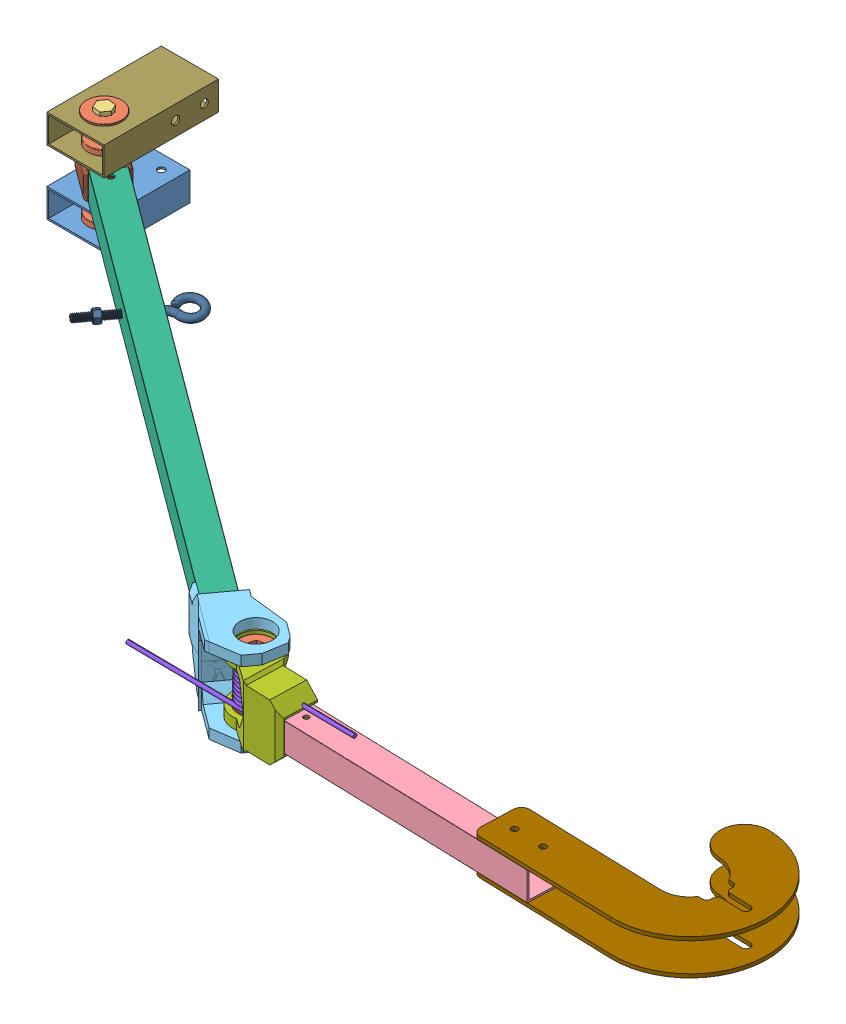
SolidWorks assembly Climber vsomething with fold back, configuration Default. Lengths in mm.
Overall size (917.13 131.37 455.28).
18 component instances, 12 part files, 20 mates.
Components (placement in the parent):
- Climb Mount small-1: Climb Mount small [Default] at origin size (50.8 25.4 76.2)
- am-2986 FR8ZZ Hex Bearing.step-1: am-2986 FR8ZZ Hex Bearing.step [Default] at (0 -6.2967 50.8) x (0.594647 0 -0.803987) z (0 -1 0) size (31.12 31.12 7.93)
- Climb axle-1: Climb axle [Default] at (0 -14.224 50.8) x (0.594647 0 -0.803987) z (0 1 0) size (14.66 12.7 88.9)
- ClimberRev2 back-1: ClimberRev2 back [Default] at (698.9971 17.3884 404.1141) x (0.001343 0.993572 -0.113195) z (0.99993 0 0.011862) size (90.91 362.58 883.75)
  - 1x1x20 box extrusion for climber-4: 1x1x20 box extrusion for climber [Default] at (0.1627 -18.2144 -212.2666) x (0.993572 0.113203 0) z (-0.002183 0.019159 0.999814) size (25.4 25.4 254)
  - Climber Insert Rev3 Outer-3: Climber Insert Rev3 Outer [Default] at (4.2736 -50.8774 -314.6587) x (0.993572 0.113203 0) z (0.066232 -0.581307 -0.810985) size (75.39 53.74 112.86)
  - 1x1x20 box extrusion for climber upper-3: 1x1x20 box extrusion for climber upper [Default] at (25.7469 -43.0175 -269.2161) x (-0.993572 -0.113203 0) z (0.066232 -0.581307 -0.810985) size (25.4 25.4 508)
  - Climber Insert Rev3 Inner-1: Climber Insert Rev3 Inner [Default] at (10.0811 -4.6349 -161.6957) x (0.993572 0.113203 0) z (0.002183 -0.019159 -0.999814) size (55.21 53.46 97.31)
  - 9271K126_Torsion Spring.step-2: 9271K126_Torsion Spring.step [Default] at (27.3298 -21.5529 -237.4141) x (-0.99171 -0.121767 -0.041038) z (-0.040732 -0.005001 0.999158) size (42.85 30.25 203.17)
  - am-2986 FR8ZZ Hex Bearing.step-1: am-2986 FR8ZZ Hex Bearing.step [Default] at (-12.7535 -26.1049 -238.3356) x (0 0 -1) z (0.993572 0.113203 0) size (31.12 31.12 7.93)
  - am-2986 FR8ZZ Hex Bearing.step-2: am-2986 FR8ZZ Hex Bearing.step [Default] at (37.1602 -20.418 -238.3356) x (0.109137 -0.957884 0.265609) z (-0.993572 -0.113203 0) size (31.12 31.12 7.93)
  - Candy cane claw-1: Candy cane claw [Default] at (24.6702 -22.9619 -8.8843) x (-0.113182 0.993387 -0.019283) z (0.993572 0.113203 0) size (137.16 195.58 3.17)
  - Candy cane claw-2: Candy cane claw [Default] at (-3.7211 -26.1967 -8.8843) x (-0.113182 0.993387 -0.019283) z (0.993572 0.113203 0) size (137.16 195.58 3.17)
  - 9489T21_Routing Eyebolt with Nut - Not for Lifting-1: 9489T21_Routing Eyebolt with Nut - Not for Lifting [9489T21] at (40.9191 -274.3463 -556.3019) x (0.205015 -0.559666 -0.802958) z (-0.974444 -0.193664 -0.113815) size (25.4 89.57 11)
- End Bearing Holder back-1: End Bearing Holder back [Default] at (25.5266 26.9875 69.68) x (-0.594647 0 0.803987) z (0 -1 0) size (31.75 57.15 22.23)
- Climb Mount large-1: Climb Mount large [Default] at (0 57.15 -25.4) size (50.8 25.4 101.6)
- am-2986 FR8ZZ Hex Bearing.step-2: am-2986 FR8ZZ Hex Bearing.step [Default] at (0 63.4467 50.8) x (-0.837169 0 -0.546944) z (0 1 0) size (31.12 31.12 7.93)
- am-2986 FR8ZZ Hex Bearing.step-3: am-2986 FR8ZZ Hex Bearing.step [Default] at (0 50.8533 50.8) x (1 0 0) z (0 -1 0) size (31.12 31.12 7.93)
Mates (geometry in assembly coordinates):
- Coincident4: coincident anti-aligned: plane of Climb Mount small-1 through (25.4 -12.7 76.2) normal (0 -1 0); plane of am-2986 FR8ZZ Hex Bearing.step-1 through (8.3072 -12.7 39.5683) normal (0 1 0)
- Concentric3: concentric anti-aligned: cylinder of Climb Mount small-1 through (0 12.7 50.8) axis (0 -1 0) radius 14.2875; cylinder of am-2986 FR8ZZ Hex Bearing.step-1 through (0 -14.224 50.8) axis (0 1 0) radius 14.2875
- Coincident7: coincident anti-aligned: plane of Climb axle-1 through (2.9252 74.676 57.5236) normal (0.803987 0 0.594647); plane of am-2986 FR8ZZ Hex Bearing.step-1 through (2.9252 -14.224 57.5236) normal (-0.803987 0 -0.594647)
- Coincident8: coincident anti-aligned: plane of Climb axle-1 through (4.3602 74.676 44.9049) normal (0.112985 0 -0.993597); plane of am-2986 FR8ZZ Hex Bearing.step-1 through (4.3602 -14.224 44.9049) normal (-0.112985 0 0.993597)
- Coincident11: coincident anti-aligned: plane of Climb axle-1 through (-2.9252 74.676 44.0764) normal (-0.803987 0 -0.594647); plane of End Bearing Holder back-1 through (-7.2854 38.1 49.9716) normal (0.803987 0 0.594647)
- Coincident12: coincident anti-aligned: plane of Climb axle-1 through (-7.2854 74.676 49.9716) normal (-0.916973 0 0.39895); plane of End Bearing Holder back-1 through (-4.3602 38.1 56.6951) normal (0.916973 0 -0.39895)
- Coincident15: coincident anti-aligned: plane of ClimberRev2 back-1/1x1x20 box extrusion for climber upper-3 through (8.7 38.1 71.0564) normal (0.594647 0 -0.803987); plane of End Bearing Holder back-1 through (24.0239 15.875 82.3903) normal (-0.594647 0 0.803987)
- Coincident16: coincident anti-aligned: plane of ClimberRev2 back-1/1x1x20 box extrusion for climber upper-3 through (8.7 38.1 71.0564) normal (0 -1 0); plane of End Bearing Holder back-1 through (37.2399 38.1 64.5217) normal (0 1 0)
- Coincident17: coincident: plane of ClimberRev2 back-1/1x1x20 box extrusion for climber upper-3; plane of End Bearing Holder back-1
- Tangent1: tangent aligned: plane of ClimberRev2 back-1/1x1x20 box extrusion for climber upper-3 through (22.7089 39.4335 52.1157) normal (-0.803987 0 -0.594647); cylinder of End Bearing Holder back-1 through (25.4685 15.875 52.6561) axis (0 1 0) radius 2.54
- Distance4: distance = 3.175 mm anti-aligned: plane of End Bearing Holder back-1 through (37.2399 15.875 64.5217) normal (0 -1 0); plane of Climb Mount small-1 through (25.4 12.7 76.2) normal (0 1 0)
- Coincident20: coincident aligned: plane of am-2986 FR8ZZ Hex Bearing.step-1 through (9.2512 -14.224 38.292) normal (0 -1 0); plane of Climb axle-1 through (0 -14.224 50.8) normal (0 -1 0)
- Coincident21: coordinate: point of Climb Mount small-1
- Concentric4: concentric anti-aligned: cylinder of Climb Mount large-1 through (0 69.85 50.8) axis (0 -1 0) radius 14.2875; cylinder of am-2986 FR8ZZ Hex Bearing.step-3 through (0 42.926 50.8) axis (0 1 0) radius 14.2875
- Concentric5: concentric aligned: cylinder of Climb Mount large-1 through (0 69.85 50.8) axis (0 -1 0) radius 14.2875; cylinder of am-2986 FR8ZZ Hex Bearing.step-2 through (0 71.374 50.8) axis (0 -1 0) radius 14.2875
- Coincident23: coincident anti-aligned: plane of Climb Mount large-1 through (25.4 44.45 76.2) normal (0 -1 0); plane of am-2986 FR8ZZ Hex Bearing.step-3 through (13.97 44.45 50.8) normal (0 1 0)
- Coincident24: coincident anti-aligned: plane of Climb Mount large-1 through (25.4 69.85 76.2) normal (0 1 0); plane of am-2986 FR8ZZ Hex Bearing.step-2 through (-11.6953 69.85 43.1592) normal (0 -1 0)
- Coincident25: coincident aligned: plane of Climb Mount small-1 through (0 0 76.2) normal (0 0 1); plane of Climb Mount large-1 through (0 57.15 76.2) normal (0 0 1)
- Coincident27: coincident aligned: plane of Climb Mount small-1 through (25.4 -12.7 76.2) normal (1 0 0); plane of Climb Mount large-1 through (25.4 44.45 76.2) normal (1 0 0)
- Distance5: distance = 31.75 mm anti-aligned: plane of Climb Mount small-1 through (25.4 12.7 76.2) normal (0 1 0); plane of Climb Mount large-1 through (25.4 44.45 76.2) normal (0 -1 0)
